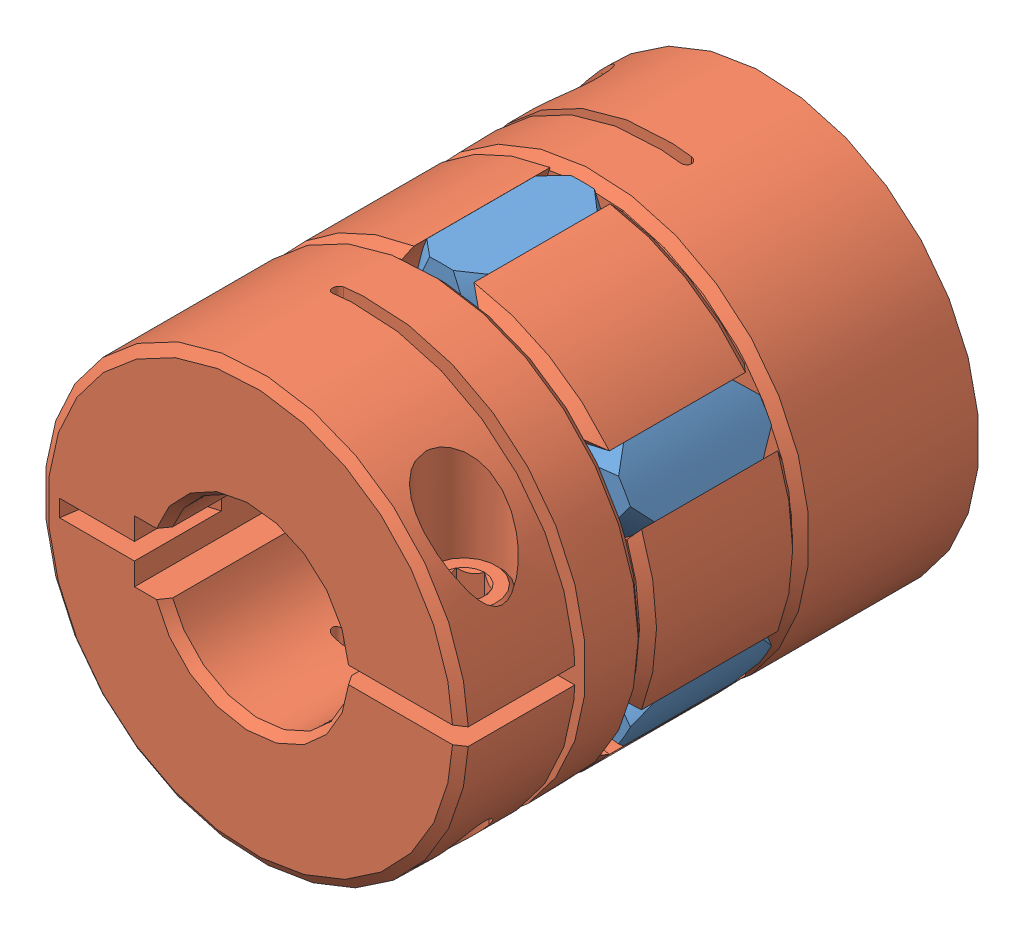
SolidWorks assembly 18-18mm Misalinemnt coupler, configuration Default. Lengths in mm.
Overall size (41.3 42.02 51.03).
3 component instances, 2 part files, 6 mates.
Components (placement in the parent):
- 9845T210_VIBRATE-DAMPING PRECISION FLEXIBLE SHAFT CPLG-1: 9845T210_VIBRATE-DAMPING PRECISION FLEXIBLE SHAFT CPLG [9845T21] at (14.3644 23.4902 31.8678) size (38.38 42 16.93)
- 9845T471_VIBRATE-DAMPING PRECISION FLEXIBLE SHAFT COUPLING-1: 9845T471_VIBRATE-DAMPING PRECISION FLEXIBLE SHAFT COUPLING [9845T471] at (14.3644 23.4902 23.3678) x (-1 0 0) z (0 0 -1) size (41.3 41.3 33.46)
- 9845T471_VIBRATE-DAMPING PRECISION FLEXIBLE SHAFT COUPLING-2: 9845T471_VIBRATE-DAMPING PRECISION FLEXIBLE SHAFT COUPLING [9845T471] at (14.3644 23.4902 25.3411) size (41.3 41.3 33.46)
Mates (geometry in assembly coordinates):
- Coincident3: coincident anti-aligned: plane of 9845T210_VIBRATE-DAMPING PRECISION FLEXIBLE SHAFT CPLG-1 through (14.3644 23.4902 31.8678) normal (1 0 0); plane of 9845T471_VIBRATE-DAMPING PRECISION FLEXIBLE SHAFT COUPLING-1 through (14.3644 23.4902 23.3678) normal (-1 0 0)
- Coincident5: coincident anti-aligned: plane of 9845T210_VIBRATE-DAMPING PRECISION FLEXIBLE SHAFT CPLG-1 through (14.3644 23.4902 31.8678) normal (0 0 1); plane of 9845T471_VIBRATE-DAMPING PRECISION FLEXIBLE SHAFT COUPLING-1 through (14.3644 23.4902 31.8678) normal (0 0 -1)
- Concentric1: concentric: cylinder of 9845T471_VIBRATE-DAMPING PRECISION FLEXIBLE SHAFT COUPLING-1 through (14.3644 23.4902 49.8678) axis (0 0 -1) radius 9; cylinder of 9845T471_VIBRATE-DAMPING PRECISION FLEXIBLE SHAFT COUPLING-2 through (14.3644 23.4902 -1.1589) axis (0 0 1) radius 9
- Concentric2: concentric: cone of 9845T210_VIBRATE-DAMPING PRECISION FLEXIBLE SHAFT CPLG-1 through (14.3644 23.4902 20.9742) axis (0 0 1); cylinder of 9845T471_VIBRATE-DAMPING PRECISION FLEXIBLE SHAFT COUPLING-2 through (14.3644 23.4902 -1.1589) axis (0 0 1) radius 9
- Coincident6: coincident: plane of 9845T210_VIBRATE-DAMPING PRECISION FLEXIBLE SHAFT CPLG-1 through (14.3644 23.4902 31.8678) normal (0 1 0); plane of 9845T471_VIBRATE-DAMPING PRECISION FLEXIBLE SHAFT COUPLING-2 through (14.3644 23.4902 25.3411) normal (0 1 0)
- Coincident7: coincident anti-aligned: plane of 9845T210_VIBRATE-DAMPING PRECISION FLEXIBLE SHAFT CPLG-1 through (14.3644 23.4902 16.8411) normal (0 0 -1); plane of 9845T471_VIBRATE-DAMPING PRECISION FLEXIBLE SHAFT COUPLING-2 through (14.3644 23.4902 16.8411) normal (0 0 1)
